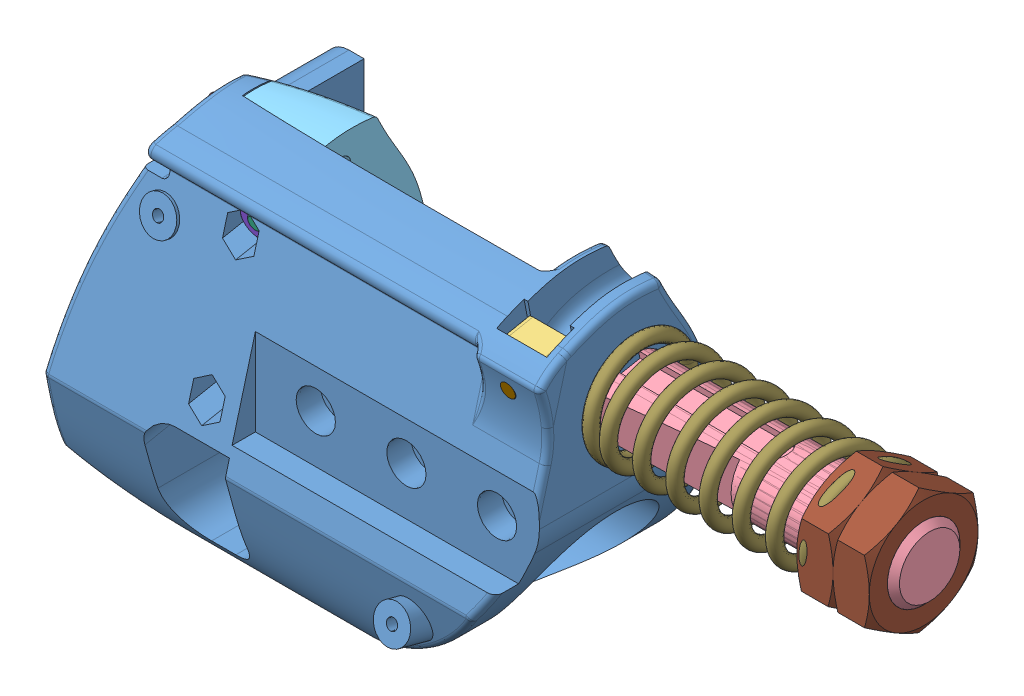
SolidWorks assembly a-motorträger-beine-rechts-v01, configuration 01. Lengths in mm.
Overall size (130.38 65.2 41.28).
22 component instances, 15 part files, 85 mates.
Components (placement in the parent):
- p-halterreferenz-rechts-v04-1: p-halterreferenz-rechts-v04 [01] at (-8 0 0) x (0 0 -1) z (1 0 0) size (41.28 65.2 84.36)
- z-jfm-0608-06-v01-1: z-jfm-0608-06-v01 [01] at (-23.3 0 0) x (-1 0 0) z (0 0 -1) size (6 12 12)
- z-induktiv-sensor-v01-1: z-induktiv-sensor-v01 [01] at (29 21.9082 7.6275) x (1 0 0) z (0 0.190809 -0.981627) size (8 16 4.7)
- z-induktiv-sensor-v01-2: z-induktiv-sensor-v01 [01] at (-25.5 8.63 4) x (0 0 -1) z (-1 0 0) size (8 16 4.7)
- p-federstössel-v01-1: p-federstössel-v01 [01] at (77.9 27.8 -1.72) x (-1 0 0) z (0 -0.190809 0.981627) size (77 12 12)
- p-halterdeckel-rechts-v02-1: p-halterdeckel-rechts-v02 [01] at (-8 0 0) x (0 0 -1) z (1 0 0) size (28.27 33.45 14.71)
- z-passschraube-misumi-4-v01-1: z-passschraube-misumi-4-v01 [01] at (-13.1 35.2829 -8.5672) x (0 -0.190809 0.981627) z (-0.839411 -0.533511 -0.103704) size (18 6.5 6.5)
- z-passschraube-misumi-4-v01-2: z-passschraube-misumi-4-v01 [01] at (-13.1 16.1412 -12.288) x (0 -0.190809 0.981627) z (-0.58333 0.797312 0.154982) size (18 6.5 6.5)
- Lock washer DIN 6799 - 7-11: Lock washer DIN 6799 - 7 [Lock washer DIN 6799 - 7] at (24 27.8 -1.72) x (0 0 1) z (-1 0 0) size (14.3 11.94 0.9)
- Hexagon Nut ISO 4032 - M2.5 - W - N-19: Hexagon Nut ISO 4032 - M2.5 - W - N [Hexagon Nut ISO 4032 - M2.5 - W - N] at (-13.1 31.8991 8.8409) x (1 0 0) z (0 -0.190809 0.981627) size (5 5.77 2)
- Hexagon Nut ISO 4032 - M2.5 - W - N-20: Hexagon Nut ISO 4032 - M2.5 - W - N [Hexagon Nut ISO 4032 - M2.5 - W - N] at (-13.1 12.7574 5.1202) x (1 0 0) z (0 -0.190809 0.981627) size (5 5.77 2)
- DIN 7991 - M3 x 8 --- 4.8C-19: DIN 7991 - M3 x 8 --- 4.8C [DIN 7991 - M3 x 8 --- 4.8C] at (-30.15 20.63 0) size (8 5.7 5.7)
- DIN 7991 - M3 x 8 --- 4.8C-20: DIN 7991 - M3 x 8 --- 4.8C [DIN 7991 - M3 x 8 --- 4.8C] at (33 34.5749 5.3527) x (0 -0.190809 0.981627) z (-0.981627 0.187303 0.036408) size (8 5.7 5.7)
- p-oese-v01-1: p-oese-v01 [01] at (-25.5 37.4 0) size (3.5 4 4)
- Hexagon Thin Nut ISO 4035 - M12 - N-19: Hexagon Thin Nut ISO 4035 - M12 - N [Hexagon Thin Nut ISO 4035 - M12 - N] at (74.9 27.8 -1.72) x (0 -0.006521 -0.999979) z (-1 0 0) size (18 20.78 6)
- Hexagon Thin Nut ISO 4035 - M12 - N-20: Hexagon Thin Nut ISO 4035 - M12 - N [Hexagon Thin Nut ISO 4035 - M12 - N] at (80.9 27.8 -1.72) x (0 0 1) z (-1 0 0) size (18 20.78 6)
- z-feder-febrotec-v01-1: z-feder-febrotec-v01 [01] at (40 28.171 -1.6479) x (1 0 0) z (0 -0.190809 0.981627) size (40.25 20.98 20.5)
- p-seil-v02-1: p-seil-v02 [01] at (-16.85 -0.1381 -7.1506) x (-1 0 0) z (0 0.190809 -0.981627) size (48.5 39 1.5)
- p-umlenkpulley-v06-1: p-umlenkpulley-v06 [01] at (-13.1 33.728 -0.5677) x (0 -0.190809 0.981627) z (-0.981627 0.187303 0.036408) size (3.6 7.15 7.15)
- p-umlenkpulley-v06-4: p-umlenkpulley-v06 [01] at (-13.1 14.5863 -4.2885) x (0 -0.190809 0.981627) z (-0.997632 0.067518 0.013124) size (3.6 7.15 7.15)
- p-umlenkpulley-v06-3: p-umlenkpulley-v06 [01] at (14.9 27.8 -1.72) x (0 -0.190809 0.981627) z (-0.981627 0.187303 0.036408) size (3.6 7.15 7.15)
- Parallel Pin ISO 2338 - 4 h6 x 10 - St-11: Parallel Pin ISO 2338 - 4 h6 x 10 - St [Parallel Pin ISO 2338 - 4 h6 x 10 - St] at (14.9 28.754 -6.6281) x (0 -0.190809 0.981627) z (-0.981627 0.187303 0.036408) size (10 4 4)
Mates (geometry in assembly coordinates):
- Deckungsgleich4: coincident anti-aligned: plane of z-jfm-0608-06-v01-1 through (-23.3 0 0) normal (0 0 -1); plane of assembly through (0 0 0) normal (0 0 1)
- Deckungsgleich22: coincident aligned: plane of p-halterreferenz-rechts-v04-1; plane of assembly through (0 0 0) normal (0 1 0)
- Deckungsgleich23: coincident anti-aligned: plane of p-halterreferenz-rechts-v04-1 through (-8 0 0) normal (0 0 -1); plane of assembly through (0 0 0) normal (0 0 1)
- Konzentrisch3: concentric aligned: cylinder of z-induktiv-sensor-v01-2 through (-30.2 20.63 0) axis (-1 0 0) radius 1.55; cylinder of p-halterreferenz-rechts-v04-1 through (38.3169 20.63 0) axis (-1 0 0) radius 1.23
- Deckungsgleich25: coincident aligned: plane of z-induktiv-sensor-v01-2; plane of p-halterreferenz-rechts-v04-1 through (-8 0 0) normal (0 0 -1)
- Deckungsgleich26: coincident anti-aligned: plane of z-induktiv-sensor-v01-2 through (-25.5 8.63 4) normal (1 0 0); plane of p-halterreferenz-rechts-v04-1 through (-25.5 0 0) normal (-1 0 0)
- Konzentrisch4: concentric aligned: cylinder of p-halterreferenz-rechts-v04-1 through (-39.3597 27.8 -1.72) axis (1 0 0) radius 6.125; cylinder of p-federstössel-v01-1 through (77.9 27.8 -1.72) axis (1 0 0) radius 6
- Parallel3: parallel anti-aligned: plane of p-halterreferenz-rechts-v04-1 through (-39.3597 22.4213 -4.6501) normal (0 0.190809 -0.981627); plane of p-federstössel-v01-1 through (65.9 20.8194 -5.1143) normal (0 -0.190809 0.981627)
- Deckungsgleich32: coincident aligned: plane of p-halterreferenz-rechts-v04-1; plane of p-halterdeckel-rechts-v02-1
- Deckungsgleich33: coincident anti-aligned: plane of p-halterdeckel-rechts-v02-1 through (-8 0 0) normal (0 0 -1); plane of assembly through (0 0 0) normal (0 0 1)
- Deckungsgleich34: coincident aligned: plane of p-halterdeckel-rechts-v02-1 through (-8 0 0) normal (1 0 0); plane of p-halterreferenz-rechts-v04-1 through (-8 0 0) normal (1 0 0)
- Konzentrisch5: concentric aligned: cylinder of p-halterdeckel-rechts-v02-1 through (-13.1 36.3949 -14.2879) axis (0 0.190809 -0.981627) radius 2.075; cylinder of z-passschraube-misumi-4-v01-1 through (-13.1 35.2829 -8.5672) axis (0 0.190809 -0.981627) radius 2
- Deckungsgleich35: coincident anti-aligned: plane of p-halterdeckel-rechts-v02-1 through (-13.1 2.3168 -11.919) normal (0 0.190809 -0.981627); plane of z-passschraube-misumi-4-v01-1 through (-14.8664 37.3885 -5.1018) normal (0 -0.190809 0.981627)
- Konzentrisch7: concentric aligned: cylinder of p-halterdeckel-rechts-v02-1 through (-13.1 17.4154 -18.843) axis (0 0.190809 -0.981627) radius 2.075; cylinder of z-passschraube-misumi-4-v01-2 through (-13.1 16.1412 -12.288) axis (0 0.190809 -0.981627) radius 2
- Deckungsgleich36: coincident anti-aligned: plane of p-halterdeckel-rechts-v02-1 through (-13.1 2.3168 -11.919) normal (0 0.190809 -0.981627); plane of z-passschraube-misumi-4-v01-2 through (-10.4602 17.4298 -8.9813) normal (0 -0.190809 0.981627)
- Konzentrisch9: concentric anti-aligned: cylinder of p-federstössel-v01-1 through (77.9 27.8 -1.72) axis (1 0 0) radius 3.5; cylinder of Lock washer DIN 6799 - 7-11 through (24.9 27.8 -1.72) axis (-1 0 0) radius 3.5
- Deckungsgleich40: coincident anti-aligned: plane of p-federstössel-v01-1 through (24.9 21.9102 -2.8649) normal (-1 0 0); plane of Lock washer DIN 6799 - 7-11 through (24.9 27.8 -1.72) normal (1 0 0)
- Konzentrisch10: concentric anti-aligned: cylinder of p-halterreferenz-rechts-v04-1 through (-13.1 27.2158 32.9346) axis (0 0.190809 -0.981627) radius 1.5; cylinder of Hexagon Nut ISO 4032 - M2.5 - W - N-19 through (-13.1 32.2808 6.8777) axis (0 -0.190809 0.981627) radius 1.025
- Parallel4: parallel anti-aligned: plane of p-halterreferenz-rechts-v04-1 through (-15.7 28.6893 33.221) normal (0.5 -0.850114 -0.165245); plane of Hexagon Nut ISO 4032 - M2.5 - W - N-19 through (-13.1 35.1145 7.4285) normal (-0.5 0.850114 0.165245)
- Deckungsgleich42: coincident anti-aligned: plane of p-halterreferenz-rechts-v04-1 through (-8 -0.1129 0.581) normal (0 -0.190809 0.981627); plane of Hexagon Nut ISO 4032 - M2.5 - W - N-19 through (-13.1 35.1145 7.4285) normal (0 0.190809 -0.981627)
- Konzentrisch11: concentric anti-aligned: cylinder of p-halterreferenz-rechts-v04-1 through (-13.1 8.0741 29.2138) axis (0 0.190809 -0.981627) radius 1.5; cylinder of Hexagon Nut ISO 4032 - M2.5 - W - N-20 through (-13.1 13.139 3.1569) axis (0 -0.190809 0.981627) radius 1.025
- Parallel5: parallel anti-aligned: plane of p-halterreferenz-rechts-v04-1 through (-15.7 9.5476 29.5002) normal (0.5 -0.850114 -0.165245); plane of Hexagon Nut ISO 4032 - M2.5 - W - N-20 through (-13.1 15.9727 3.7077) normal (-0.5 0.850114 0.165245)
- Deckungsgleich44: coincident anti-aligned: plane of p-halterreferenz-rechts-v04-1 through (-8 -0.1129 0.581) normal (0 -0.190809 0.981627); plane of Hexagon Nut ISO 4032 - M2.5 - W - N-20 through (-13.1 15.9727 3.7077) normal (0 0.190809 -0.981627)
- Konzentrisch12: concentric aligned: cylinder of z-induktiv-sensor-v01-2 through (-30.2 20.63 0) axis (-1 0 0) radius 1.55; cylinder of DIN 7991 - M3 x 8 --- 4.8C-19 through (-30.15 20.63 0) axis (-1 0 0) radius 1.5
- Deckungsgleich45: coincident aligned: cone of z-induktiv-sensor-v01-2 through (-28.5 20.63 0) axis (1 0 0); cone of DIN 7991 - M3 x 8 --- 4.8C-19 through (-29.8 20.63 0) axis (1 0 0)
- Konzentrisch14: concentric aligned: cylinder of z-induktiv-sensor-v01-1 through (33 34.5845 5.3036) axis (0 0.190809 -0.981627) radius 1.55; cylinder of DIN 7991 - M3 x 8 --- 4.8C-20 through (33 34.5749 5.3527) axis (0 0.190809 -0.981627) radius 1.5
- Deckungsgleich46: coincident aligned: cone of z-induktiv-sensor-v01-1 through (33 34.2601 6.9724) axis (0 -0.190809 0.981627); cone of DIN 7991 - M3 x 8 --- 4.8C-20 through (33 34.5082 5.6962) axis (0 -0.190809 0.981627)
- Konzentrisch16: concentric anti-aligned: cylinder of p-halterreferenz-rechts-v04-1 through (-21.3635 37.4 0) axis (1 0 0) radius 2.15; cylinder of p-oese-v01-1 through (-25.5 37.4 0) axis (-1 0 0) radius 2
- Deckungsgleich47: coincident anti-aligned: plane of p-halterreferenz-rechts-v04-1 through (-25.5 39.55 0) normal (1 0 0); plane of p-oese-v01-1 through (-25.5 39.4 0) normal (-1 0 0)
- Konzentrisch17: concentric anti-aligned: cylinder of p-federstössel-v01-1 through (77.9 27.8 -1.72) axis (1 0 0) radius 6; cylinder of Hexagon Thin Nut ISO 4035 - M12 - N-19 through (80.9 27.8 -1.72) axis (-1 0 0) radius 5.1
- Abstand16: distance = 7 mm aligned: plane of Hexagon Thin Nut ISO 4035 - M12 - N-19 through (80.9 17.4079 -1.6522) normal (1 0 0); plane of p-federstössel-v01-1 through (87.9 21.9102 -2.8649) normal (1 0 0)
- Konzentrisch19: concentric anti-aligned: cylinder of p-federstössel-v01-1 through (77.9 27.8 -1.72) axis (1 0 0) radius 6; cylinder of Hexagon Thin Nut ISO 4035 - M12 - N-20 through (86.9 27.8 -1.72) axis (-1 0 0) radius 5.1
- Deckungsgleich49: coincident anti-aligned: plane of Hexagon Thin Nut ISO 4035 - M12 - N-19 through (80.9 17.4079 -1.6522) normal (1 0 0); plane of Hexagon Thin Nut ISO 4035 - M12 - N-20 through (80.9 38.1923 -1.72) normal (-1 0 0)
- Deckungsgleich50: coincident aligned: plane of p-federstössel-v01-1 through (77.9 27.8 -1.72) normal (0 -0.190809 0.981627); plane of z-feder-febrotec-v01-1 through (40 28.171 -1.6479) normal (0 -0.190809 0.981627)
- Abstand17: distance = 3 mm aligned: plane of z-feder-febrotec-v01-1; plane of p-halterreferenz-rechts-v04-1 through (37 0 0) normal (1 0 0)
- Konzentrisch20: concentric anti-aligned: cylinder of z-passschraube-misumi-4-v01-1 through (-13.1 35.2829 -8.5672) axis (0 0.190809 -0.981627) radius 2; cylinder of p-umlenkpulley-v06-1 through (-13.1 31.4085 11.3649) axis (0 -0.190809 0.981627) radius 2.075
- Deckungsgleich52: coincident aligned: plane of p-federstössel-v01-1 through (77.9 27.8 -1.72) normal (0 -0.190809 0.981627); plane of p-umlenkpulley-v06-1
- Konzentrisch21: concentric anti-aligned: cylinder of z-passschraube-misumi-4-v01-2 through (-13.1 16.1412 -12.288) axis (0 0.190809 -0.981627) radius 2; cylinder of p-umlenkpulley-v06-4 through (-13.1 12.2668 7.6441) axis (0 -0.190809 0.981627) radius 2.075
- Deckungsgleich53: coincident aligned: plane of p-umlenkpulley-v06-1 through (-12.4179 37.5163 -1.665) normal (0 0.190809 -0.981627); plane of p-umlenkpulley-v06-4 through (-12.8541 18.4307 -5.3749) normal (0 0.190809 -0.981627)
- Konzentrisch22: concentric: cylinder of z-passschraube-misumi-4-v01-1 through (-13.1 35.2829 -8.5672) axis (0 0.190809 -0.981627) radius 2; point of p-seil-v02-1
- Konzentrisch23: concentric: cylinder of z-passschraube-misumi-4-v01-2 through (-13.1 16.1412 -12.288) axis (0 0.190809 -0.981627) radius 2; point of p-seil-v02-1
- Deckungsgleich57: coincident anti-aligned: plane of p-seil-v02-1 through (-16.85 -0.1381 -7.1506) normal (0 0.190809 -0.981627); plane of p-umlenkpulley-v06-1
- Deckungsgleich59: coincident anti-aligned: plane of p-halterreferenz-rechts-v04-1 through (-8 0 0) normal (0 0 -1); plane of assembly through (0 0 0) normal (0 0 1)
- Abstand18: distance = 8 mm aligned: plane of assembly through (0 0 0) normal (1 0 0); plane of p-halterreferenz-rechts-v04-1 through (-8 0 0) normal (1 0 0)
- Konzentrisch24: concentric aligned: cylinder of p-halterreferenz-rechts-v04-1 through (0 0 0) axis (1 0 0) radius 4.075; cylinder of z-jfm-0608-06-v01-1 through (-23.3 0 0) axis (1 0 0) radius 4
- Deckungsgleich64: coincident anti-aligned: plane of p-halterreferenz-rechts-v04-1 through (-24.3 6.25 0) normal (1 0 0); plane of z-jfm-0608-06-v01-1 through (-24.3 6 0) normal (-1 0 0)
- Parallel6: parallel aligned: plane of z-jfm-0608-06-v01-1; plane of assembly through (0 0 0) normal (0 1 0)
- Konzentrisch25: concentric aligned: cylinder of p-halterreferenz-rechts-v04-1 through (33 29.1408 33.3088) axis (0 0.190809 -0.981627) radius 1.23; cylinder of z-induktiv-sensor-v01-1 through (33 34.5845 5.3036) axis (0 0.190809 -0.981627) radius 1.55
- Deckungsgleich65: coincident anti-aligned: plane of p-halterreferenz-rechts-v04-1 through (28.85 41.4425 11.4246) normal (0 0.190809 -0.981627); plane of z-induktiv-sensor-v01-1 through (29 21.9082 7.6275) normal (0 -0.190809 0.981627)
- Parallel7: parallel anti-aligned: plane of p-halterreferenz-rechts-v04-1 through (37.15 0 0) normal (-1 0 0); plane of z-induktiv-sensor-v01-1 through (37 22.805 3.0139) normal (1 0 0)
- Konzentrisch26: concentric aligned: cylinder of p-federstössel-v01-1 through (14.9 29.1357 -8.5914) axis (0 -0.190809 0.981627) radius 2; cylinder of p-umlenkpulley-v06-3 through (14.9 25.4805 10.2126) axis (0 -0.190809 0.981627) radius 2.075
- Deckungsgleich69: coincident aligned: plane of p-federstössel-v01-1 through (77.9 27.8 -1.72) normal (0 -0.190809 0.981627); plane of p-umlenkpulley-v06-3
- Konzentrisch27: concentric anti-aligned: cylinder of p-federstössel-v01-1 through (14.9 29.1357 -8.5914) axis (0 -0.190809 0.981627) radius 2; cylinder of Parallel Pin ISO 2338 - 4 h6 x 10 - St-11 through (14.9 29.9657 -12.8615) axis (0 0.190809 -0.981627) radius 2
- Abstand19: distance = 5 mm anti-aligned: plane of p-federstössel-v01-1 through (77.9 27.8 -1.72) normal (0 -0.190809 0.981627); plane of Parallel Pin ISO 2338 - 4 h6 x 10 - St-11 through (15.2494 30.5186 -6.2851) normal (0 0.190809 -0.981627)
- Abstand20: distance = 28 mm aligned: plane of p-federstössel-v01-1; plane of p-halterreferenz-rechts-v04-1 through (-13.1 0 0) normal (-1 0 0)
- Konzentrisch190: concentric aligned: cylinder of p-halterreferenz-rechts-v04-1 through (38.3169 20.63 0) axis (-1 0 0) radius 1.23; cylinder of z-induktiv-sensor-v01-2 through (-30.2 20.63 0) axis (-1 0 0) radius 1.55
- Deckungsgleich158: coincident anti-aligned: plane of p-halterreferenz-rechts-v04-1 through (-25.5 0 0) normal (-1 0 0); plane of z-induktiv-sensor-v01-2 through (-25.5 8.63 4) normal (1 0 0)
- Konzentrisch191: concentric aligned: cylinder of p-halterreferenz-rechts-v04-1 through (-39.3597 27.8 1.72) axis (1 0 0) radius 6.05; cylinder of p-federstössel-v01-1 through (71.9 27.8 1.72) axis (1 0 0) radius 6
- Parallel16: parallel anti-aligned: plane of p-halterreferenz-rechts-v04-1; plane of p-federstössel-v01-1
- Konzentrisch192: concentric aligned: cylinder of p-halterdeckel-rechts-v02-1 through (-13.1 36.3949 14.2879) axis (0 0.190809 0.981627) radius 2; cylinder of z-passschraube-misumi-4-v01-1 through (-13.1 35.2829 8.5672) axis (0 0.190809 0.981627) radius 2
- Deckungsgleich159: coincident anti-aligned: plane of p-halterdeckel-rechts-v02-1; plane of z-passschraube-misumi-4-v01-1
- Konzentrisch193: concentric aligned: cylinder of p-halterdeckel-rechts-v02-1 through (-13.1 17.4154 18.843) axis (0 0.190809 0.981627) radius 2; cylinder of z-passschraube-misumi-4-v01-2 through (-13.1 16.1412 12.288) axis (0 0.190809 0.981627) radius 2
- Deckungsgleich160: coincident anti-aligned: plane of p-halterdeckel-rechts-v02-1; plane of z-passschraube-misumi-4-v01-2
- Konzentrisch194: concentric aligned: cylinder of p-federstössel-v01-1 through (71.9 27.8 1.72) axis (1 0 0) radius 3.5; cylinder of Lock washer DIN 6799 - 7-11 through (18 27.8 1.72) axis (1 0 0) radius 3.5
- Konzentrisch195: concentric anti-aligned: cylinder of p-halterreferenz-rechts-v04-1 through (-13.1 27.2158 -32.9346) axis (0 0.190809 0.981627) radius 1.5; cylinder of Hexagon Nut ISO 4032 - M2.5 - W - N-19 through (-13.1 32.2808 -6.8777) axis (0 -0.190809 -0.981627) radius 1.025
- Deckungsgleich161: coincident anti-aligned: plane of p-halterreferenz-rechts-v04-1 through (-8 -0.1129 -0.581) normal (0 -0.190809 -0.981627); plane of Hexagon Nut ISO 4032 - M2.5 - W - N-19 through (-13.1 35.1145 -7.4285) normal (0 0.190809 0.981627)
- Konzentrisch196: concentric anti-aligned: cylinder of p-halterreferenz-rechts-v04-1 through (-13.1 8.0741 -29.2138) axis (0 0.190809 0.981627) radius 1.5; cylinder of Hexagon Nut ISO 4032 - M2.5 - W - N-20 through (-13.1 13.139 -3.1569) axis (0 -0.190809 -0.981627) radius 1.025
- Deckungsgleich162: coincident anti-aligned: plane of p-halterreferenz-rechts-v04-1 through (-8 -0.1129 -0.581) normal (0 -0.190809 -0.981627); plane of Hexagon Nut ISO 4032 - M2.5 - W - N-20 through (-13.1 15.9727 -3.7077) normal (0 0.190809 0.981627)
- Konzentrisch197: concentric aligned: cylinder of z-induktiv-sensor-v01-2 through (-30.2 20.63 0) axis (-1 0 0) radius 1.55; cylinder of DIN 7991 - M3 x 8 --- 4.8C-19 through (-30.15 20.63 0) axis (-1 0 0) radius 1.5
- Deckungsgleich163: coincident aligned: cone of z-induktiv-sensor-v01-2 through (-28.5 20.63 0) axis (1 0 0); cone of DIN 7991 - M3 x 8 --- 4.8C-19 through (-29.8 20.63 0) axis (1 0 0)
- Konzentrisch198: concentric aligned: cylinder of z-induktiv-sensor-v01-1 through (33 34.5845 -5.3036) axis (0 0.190809 0.981627) radius 1.55; cylinder of DIN 7991 - M3 x 8 --- 4.8C-20 through (33 34.5749 -5.3527) axis (0 0.190809 0.981627) radius 1.5
- Deckungsgleich164: coincident aligned: cone of z-induktiv-sensor-v01-1 through (33 34.2601 -6.9724) axis (0 -0.190809 -0.981627); cone of DIN 7991 - M3 x 8 --- 4.8C-20 through (33 34.5082 -5.6962) axis (0 -0.190809 -0.981627)
- Konzentrisch199: concentric anti-aligned: cylinder of p-halterreferenz-rechts-v04-1 through (-21.3635 37.4 0) axis (1 0 0) radius 2.05; cylinder of p-oese-v01-1 through (-25.5 37.4 0) axis (-1 0 0) radius 2
- Deckungsgleich165: coincident anti-aligned: plane of p-halterreferenz-rechts-v04-1 through (-25.5 39.45 0) normal (1 0 0); plane of p-oese-v01-1 through (-25.5 39.4 0) normal (-1 0 0)
- Konzentrisch200: concentric aligned: cylinder of p-federstössel-v01-1 through (71.9 27.8 1.72) axis (1 0 0) radius 6; cylinder of Hexagon Thin Nut ISO 4035 - M12 - N-19 through (67.8963 27.8 1.72) axis (1 0 0) radius 5.1
- Konzentrisch201: concentric aligned: cylinder of p-federstössel-v01-1 through (71.9 27.8 1.72) axis (1 0 0) radius 6; cylinder of Hexagon Thin Nut ISO 4035 - M12 - N-20 through (73.8963 27.8 1.72) axis (1 0 0) radius 5.1
- Konzentrisch202: concentric anti-aligned: cylinder of z-passschraube-misumi-4-v01-1 through (-13.1 35.2829 8.5672) axis (0 0.190809 0.981627) radius 2; cylinder of p-umlenkpulley-v06-1 through (-13.1 31.4085 -11.3649) axis (0 -0.190809 -0.981627) radius 2
- Konzentrisch203: concentric anti-aligned: cylinder of z-passschraube-misumi-4-v01-2 through (-13.1 16.1412 12.288) axis (0 0.190809 0.981627) radius 2; cylinder of p-umlenkpulley-v06-4 through (-13.1 12.2668 -7.6441) axis (0 -0.190809 -0.981627) radius 2
- Deckungsgleich166: coincident aligned: plane of p-umlenkpulley-v06-1 through (-12.4322 37.444 1.6791) normal (0 0.190809 0.981627); plane of p-umlenkpulley-v06-4 through (-12.8593 18.3573 5.3892) normal (0 0.190809 0.981627)
- Konzentrisch204: concentric aligned: cylinder of p-halterreferenz-rechts-v04-1 through (0 0 0) axis (1 0 0) radius 4; cylinder of z-jfm-0608-06-v01-1 through (-23.1 0 0) axis (1 0 0) radius 4
- Deckungsgleich167: coincident anti-aligned: plane of p-halterreferenz-rechts-v04-1 through (-24.1 6.25 0) normal (1 0 0); plane of z-jfm-0608-06-v01-1 through (-24.1 6 0) normal (-1 0 0)
- Konzentrisch205: concentric aligned: cylinder of p-halterreferenz-rechts-v04-1 through (33 29.1408 -33.3088) axis (0 0.190809 0.981627) radius 1.23; cylinder of z-induktiv-sensor-v01-1 through (33 34.5845 -5.3036) axis (0 0.190809 0.981627) radius 1.55
- Deckungsgleich168: coincident anti-aligned: plane of p-halterreferenz-rechts-v04-1 through (28.85 41.4425 -11.4246) normal (0 0.190809 0.981627); plane of z-induktiv-sensor-v01-1 through (37 21.9082 -7.6275) normal (0 -0.190809 -0.981627)
- Konzentrisch206: concentric aligned: cylinder of p-federstössel-v01-1 through (8.9 29.1357 8.5914) axis (0 -0.190809 -0.981627) radius 2; cylinder of p-umlenkpulley-v06-3 through (8.9 25.4805 -10.2126) axis (0 -0.190809 -0.981627) radius 2
- Konzentrisch207: concentric anti-aligned: cylinder of p-federstössel-v01-1 through (8.9 29.1357 8.5914) axis (0 -0.190809 -0.981627) radius 2; cylinder of Parallel Pin ISO 2338 - 4 h6 x 10 - St-11 through (8.9 29.9657 12.8615) axis (0 0.190809 0.981627) radius 2
